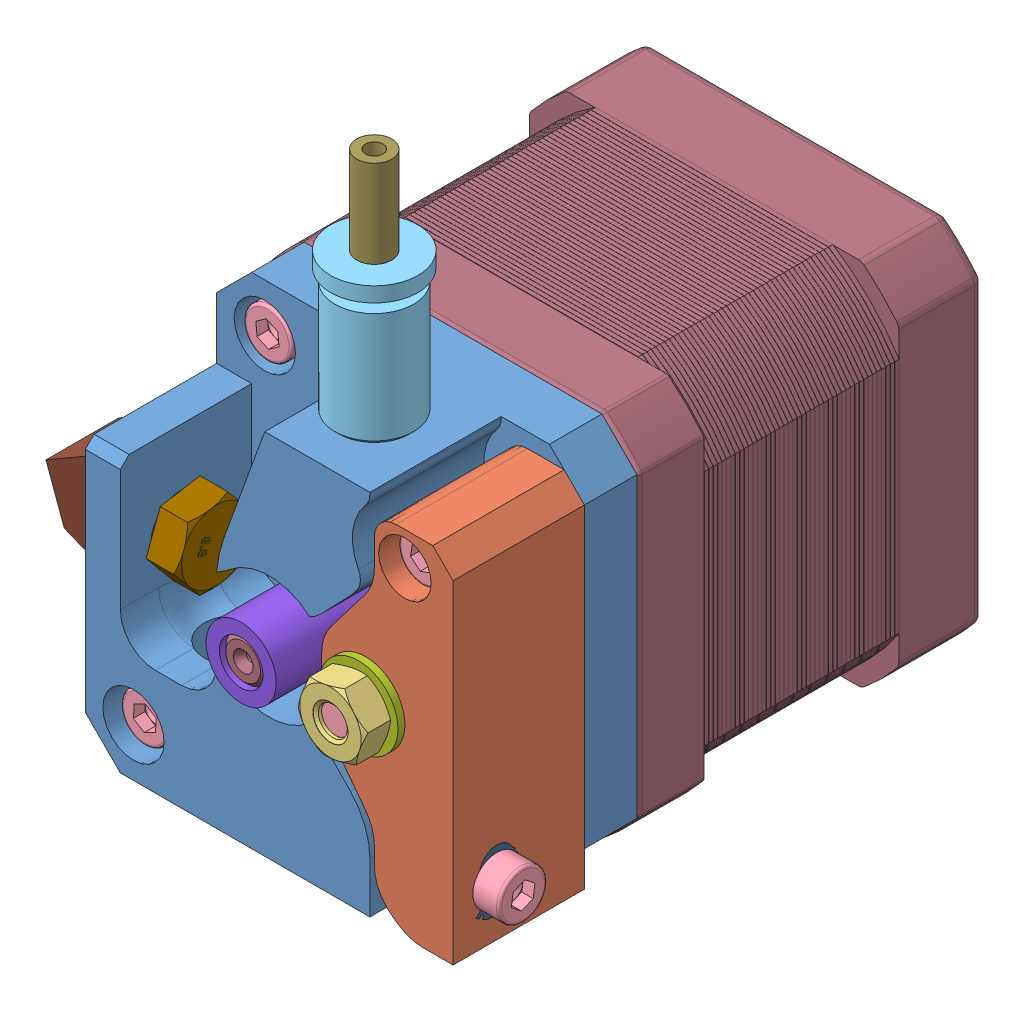
SolidWorks assembly ExtruderDD1, configuration Default. Lengths in mm.
Overall size (52.82 68.55 77.24).
21 component instances, 12 part files, 39 mates.
Components (placement in the parent):
- DD-1 extruder-1: DD-1 extruder [Default] at origin size (42 42 21)
- DD-1 Idler-1: DD-1 Idler [Default] at (21 19 1) x (0 1 0) z (0 0 1) size (40.32 15 15)
- Hex nut-1: Hex nut [M3 Hex Nut] at (-1.8851 -15.1119 -4) x (0 0 1) z (-1 0 0) size (5.5 6.35 2.4)
- Socket head cap screw-1: Socket head cap screw [M3x10] at (-15.5 15.5 -14.3) x (0 0 -1) z (0.417389 0.908728 0) size (13 5.5 5.5)
- Socket head cap screw-3: Socket head cap screw [M3x25] at (24 -15.1119 -4) x (-1 0 0) z (0 -0.78719 0.61671) size (28 5.5 5.5)
- Socket head cap screw-5: Socket head cap screw [M3x20] at (-15.5 -15.5 -0.3) x (0 0 -1) z (0.998489 -0.054943 0) size (23 5.5 5.5)
- Socket head cap screw-7: Socket head cap screw [M3x20] at (15.5 15.5 -1) x (0 0 -1) z (0.636505 0.771273 0) size (23 5.5 5.5)
- Socket head cap screw-9: Socket head cap screw [M4x15] at (11 0 -13.6) x (0 0 1) z (-0.524136 0.851635 0) size (18 7 7)
- Metalwork 2L01001-1: Metalwork 2L01001 [Default] at (4 17 -7) x (0.999567 0 0.029419) z (-0.029419 0 0.999567) size (10 20.2 10)
- 4mm Bearing SKF 624 RS 286-7798-1: 4mm Bearing SKF 624 RS 286-7798 [Default] at (11 0 -3.8) x (0 0 1) z (-0.999983 0.0059 0) size (5 13 13)
- Plain washer-14: Plain washer [M4 plain washer] at (11 0 -3) x (0 0 1) z (0.923231 0.384246 0) size (0.8 9 9)
- Plain washer-15: Plain washer [M4 plain washer] at (11 0 -9.6) x (0 0 -1) z (0.265133 -0.964212 0) size (0.8 9 9)
- MK8 hobbed gear-1: MK8 hobbed gear [Default] at (0 0 4.2) size (8 8 13)
- Plain washer-16: Plain washer [M4 plain washer] at (11 0 1) x (0 0 -1) z (1 0 0) size (0.8 9 9)
- Hex nut-5: Hex nut [M4 Hex Nut] at (11 0 1.8) x (-0.945605 0.325316 0) z (0 0 -1) size (7 8.08 3.2)
- Hex head screw-1: Hex head screw [M5X12 H] at (-13 0 -6) x (0 -0.93725 0.348659) z (0 0.348659 0.93725) size (9.24 15.87 8)
- Plain washer-13: Plain washer [M3 plain washer] at (-16.5 0 -6) x (1 0 0) z (0 -0.964212 0.265133) size (0.5 7 7)
- HNTF6-5-1: HNTF6-5 [Default] at (-21 0 -6) size (6.3 15 12.3)
- Plain washer-12: Plain washer [M3 plain washer] at (21 -15.1119 -4) size (0.5 7 7)
- PTFE tube 4mm-2mm-1: PTFE tube 4mm-2mm [Default] at (4 47.2 -7) x (1 0 0) z (0 -1 0) size (4 4 10)
- nema17 dual shaft-1: nema17 dual shaft [Default] at (-0.006 0.006 -27.5692) size (42.24 42.48 76.2)
Mates (geometry in assembly coordinates):
- Coincident1: coincident anti-aligned: plane of DD-1 extruder-1 through (0 0 -14) normal (0 0 1); plane of DD-1 Idler-1 through (21 19 -14) normal (0 0 -1)
- Concentric1: concentric anti-aligned: cylinder of DD-1 extruder-1 through (15.5 15.5 -14) axis (0 0 -1) radius 1.75; cylinder of DD-1 Idler-1 through (15.5 15.5 -14) axis (0 0 1) radius 1.3432
- Concentric5: concentric anti-aligned: cylinder of DD-1 extruder-1 through (11.5 -15.1119 -4) axis (1 0 0) radius 1.5; cylinder of Hex nut-1 through (0.5149 -15.1119 -4) axis (-1 0 0) radius 1.25
- Coincident3: coincident anti-aligned: plane of DD-1 extruder-1 through (0.5149 -11 0) normal (-1 0 0); plane of Hex nut-1 through (0.5149 -11.9365 -4) normal (1 0 0)
- Concentric6: concentric anti-aligned: cylinder of DD-1 extruder-1 through (-15.5 -15.5 -14) axis (0 0 -1) radius 1.75; cylinder of Socket head cap screw-5 through (-15.5 -15.5 31.45) axis (0 0 1) radius 1.5
- Coincident4: coincident anti-aligned: plane of DD-1 extruder-1 through (-15.5 -15.5 -3.3) normal (0 0 1); plane of Socket head cap screw-5 through (-15.3489 -12.7542 -3.3) normal (0 0 -1)
- Concentric7: concentric anti-aligned: cylinder of DD-1 extruder-1 through (-15.5 15.5 -14) axis (0 0 -1) radius 1.75; cylinder of Socket head cap screw-1 through (-15.5 15.5 17.45) axis (0 0 1) radius 1.5
- Coincident5: coincident anti-aligned: plane of DD-1 extruder-1 through (-15.5 15.5 -17.3) normal (0 0 1); plane of Socket head cap screw-1 through (-17.999 16.6478 -17.3) normal (0 0 -1)
- Concentric8: concentric aligned: cylinder of DD-1 Idler-1 through (15.5 15.5 -14) axis (0 0 1) radius 1.3432; cylinder of Socket head cap screw-7 through (15.5 15.5 30.75) axis (0 0 1) radius 1.5
- Coincident6: coincident anti-aligned: plane of DD-1 Idler-1 through (15.5 15.5 -4) normal (0 0 1); plane of Socket head cap screw-7 through (13.379 17.2504 -4) normal (0 0 -1)
- Concentric9: concentric aligned: cylinder of DD-1 extruder-1 through (11.5 -15.1119 -4) axis (1 0 0) radius 1.5; cylinder of Socket head cap screw-3 through (55.75 -15.1119 -4) axis (1 0 0) radius 1.5
- Coincident7: coincident anti-aligned: plane of DD-1 Idler-1 through (21 -21 -14) normal (1 0 0); plane of Socket head cap screw-3 through (21 -16.8079 -6.1648) normal (-1 0 0)
- Concentric10: concentric anti-aligned: cylinder of DD-1 Idler-1 through (11 0 -14) axis (0 0 1) radius 2; cylinder of Socket head cap screw-9 through (11 0 -45.35) axis (0 0 -1) radius 2
- Concentric11: concentric anti-aligned: cylinder of DD-1 extruder-1 through (4 21 -7) axis (0 1 0) radius 2.1; cylinder of Metalwork 2L01001-1 through (4 17.4905 -7) axis (0 -1 0) radius 2.5
- Coincident8: coincident anti-aligned: plane of DD-1 extruder-1 through (21 21 -14) normal (0 1 0); circle of Metalwork 2L01001-1
- Concentric12: concentric anti-aligned: cylinder of Socket head cap screw-9 through (11 0 -45.35) axis (0 0 -1) radius 2; circle of Plain washer-15
- Coincident9: coincident anti-aligned: plane of Socket head cap screw-9 through (13.9807 1.8345 -9.6) normal (0 0 1); plane of Plain washer-15 through (13.0731 0.57 -9.6) normal (0 0 -1)
- Coincident12: coincident anti-aligned: cylinder of Socket head cap screw-9 through (11 0 -45.35) axis (0 0 -1) radius 2; circle of 4mm Bearing SKF 624 RS 286-7798-1
- Coincident13: coincident anti-aligned: plane of 4mm Bearing SKF 624 RS 286-7798-1 through (11.0139 2.35 -8.8) normal (0 0 -1); plane of Plain washer-15 through (15.339 1.1931 -8.8) normal (0 0 1)
- Concentric14: concentric aligned: cylinder of Socket head cap screw-9 through (11 0 -45.35) axis (0 0 -1) radius 2; cylinder of Plain washer-14 through (11 0 -37.925) axis (0 0 -1) radius 2.15
- Coincident14: coincident anti-aligned: plane of 4mm Bearing SKF 624 RS 286-7798-1 through (11.0139 2.35 -3.8) normal (0 0 1); plane of Plain washer-14 through (12.7291 -4.1545 -3.8) normal (0 0 -1)
- Coincident16: coincident anti-aligned: plane of DD-1 Idler-1 through (11 0 -3) normal (0 0 -1); plane of Plain washer-14 through (11.8261 -1.9849 -3) normal (0 0 1)
- Concentric15: concentric anti-aligned: cylinder of Socket head cap screw-9 through (11 0 -45.35) axis (0 0 -1) radius 2; circle of Plain washer-16
- Coincident17: coincident anti-aligned: plane of DD-1 Idler-1 through (21 19 1) normal (0 0 1); plane of Plain washer-16 through (11 2.15 1) normal (0 0 -1)
- Concentric16: concentric anti-aligned: cylinder of Socket head cap screw-9 through (11 0 -45.35) axis (0 0 -1) radius 2; circle of Hex nut-5
- Coincident18: coincident anti-aligned: plane of Plain washer-16 through (11 4.5 1.8) normal (0 0 1); plane of Hex nut-5 through (12.3147 3.8216 1.8) normal (0 0 -1)
- Concentric17: concentric anti-aligned: cylinder of DD-1 extruder-1 through (-17 0 -6) axis (-1 0 0) radius 2.75; cylinder of Hex head screw-1 through (-28.5 0 -6) axis (1 0 0) radius 2.5
- Concentric18: concentric anti-aligned: cylinder of Hex head screw-1 through (-28.5 0 -6) axis (1 0 0) radius 2.5; circle of Plain washer-13
- Coincident19: coincident anti-aligned: plane of Hex head screw-1 through (-16.5 -4.329 -4.3896) normal (-1 0 0); plane of Plain washer-13 through (-16.5 0.4242 -4.4573) normal (1 0 0)
- Coincident20: coincident anti-aligned: plane of DD-1 extruder-1 through (-17 10 1) normal (1 0 0); plane of Plain washer-13 through (-17 0.928 -2.6253) normal (-1 0 0)
- Concentric19: concentric anti-aligned: cylinder of Hex head screw-1 through (-28.5 0 -6) axis (1 0 0) radius 2.5; cylinder of HNTF6-5-1 through (-27.3 0 -6) axis (-1 0 0) radius 2.067
- Coincident21: coincident anti-aligned: plane of DD-1 extruder-1 through (-21 -21 -14) normal (-1 0 0); plane of HNTF6-5-1 through (-21 1.3 -7.1011) normal (1 0 0)
- Concentric20: concentric anti-aligned: cylinder of Socket head cap screw-3 through (55.75 -15.1119 -4) axis (1 0 0) radius 1.5; circle of Plain washer-12
- Coincident22: coincident anti-aligned: plane of Socket head cap screw-3 through (21 -16.8079 -6.1648) normal (-1 0 0); plane of Plain washer-12 through (21 -13.5119 -4) normal (1 0 0)
- Concentric21: concentric anti-aligned: cylinder of Metalwork 2L01001-1 through (4 37.2 -7) axis (0 -1 0) radius 2; cylinder of PTFE tube 4mm-2mm-1 through (4 37.2 -7) axis (0 1 0) radius 1
- Coincident23: coincident anti-aligned: plane of Metalwork 2L01001-1 through (-0.909 37.2 -12.2067) normal (0 1 0); circle of PTFE tube 4mm-2mm-1
- Concentrico2: concentric aligned: cylinder of Socket head cap screw-1 through (-15.5 15.5 17.45) axis (0 0 1) radius 1.5; cylinder of nema17 dual shaft-1 through (-15.5 15.5 -25.3721) axis (0 0 1) radius 1.2319
- Coincidente1: coincident anti-aligned: plane of DD-1 extruder-1 through (0 0 -20) normal (0 0 -1); plane of nema17 dual shaft-1 through (-0.006 0.006 -20) normal (0 0 1)
- Parallelo1: parallel aligned: plane of DD-1 extruder-1 through (21 -21 -14) normal (1 0 0); plane of nema17 dual shaft-1 through (21.076 16.9764 -27.5692) normal (1 0 0)
